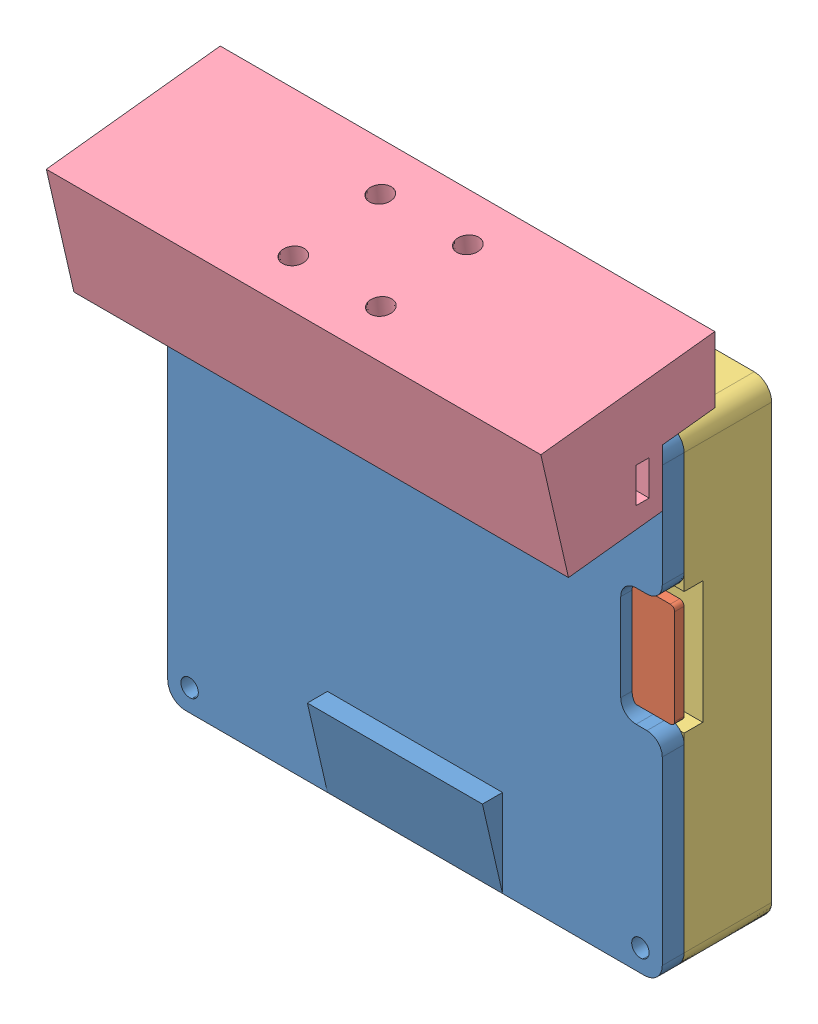
SolidWorks assembly mount assemblies, configuration Default. Lengths in mm.
Overall size (113.25 123.46 58.45).
4 component instances, 4 part files, 7 mates.
Components (placement in the parent):
- Back Plate-1: Back Plate [Default] at (-57.5189 72.9225 17.2346) x (-1 0 0) z (0 -1 0) size (113 9.6 107)
- Full Graphic Smart Controller-1: Full Graphic Smart Controller [Default] at (-57.2934 73.624 12.2346) x (-1 0 0) z (0 0 -1) size (102.9 86.75 34.7)
- Lid-1: Lid [Default] at (-57.5189 72.9225 -2.7654) x (-1 0 0) z (0 0 -1) size (113 107 20)
- Hieght part-1: Hieght part [Default] at (-57.5189 142.8795 5.2346) x (0 0.993631 0.112683) z (0 -0.112683 0.993631) size (28 113 40)
Mates (geometry in assembly coordinates):
- Coincident10: coincident anti-aligned: plane of Back Plate-1 through (-57.5189 72.9225 12.2346) normal (0 0 -1); plane of Full Graphic Smart Controller-1 through (-10.9184 116.999 12.2346) normal (0 0 1)
- Coincident11: coincident anti-aligned: plane of Back Plate-1 through (-57.5189 72.9225 12.2346) normal (0 0 -1); plane of Lid-1 through (-57.5189 72.9225 12.2346) normal (0 0 1)
- Coincident12: coincident aligned: plane of Back Plate-1 through (-1.0189 19.4225 12.2346) normal (1 0 0); plane of Lid-1 through (-1.0189 19.4225 -7.7654) normal (1 0 0)
- Coincident13: coincident aligned: plane of Back Plate-1 through (-1.0189 126.4225 12.2346) normal (0 1 0); plane of Lid-1 through (-1.0189 126.4225 -7.7654) normal (0 1 0)
- Coincident14: coincident anti-aligned: plane of Back Plate-1 through (-57.5189 72.9225 17.2346) normal (0 0 1); plane of Hieght part-1 through (-127.0189 78.3349 17.2346) normal (0 0 -1)
- Coincident16: coincident aligned: plane of Lid-1 through (-114.0189 19.4225 -7.7654) normal (-1 0 0); plane of Hieght part-1 through (-114.0189 142.8795 5.2346) normal (-1 0 0)
- Concentric1: concentric aligned: cylinder of Back Plate-1 through (-109.0189 121.4225 21.8299) axis (0 0 -1) radius 2; cylinder of Hieght part-1 through (-109.0189 121.4225 23.2346) axis (0 0 -1) radius 2
